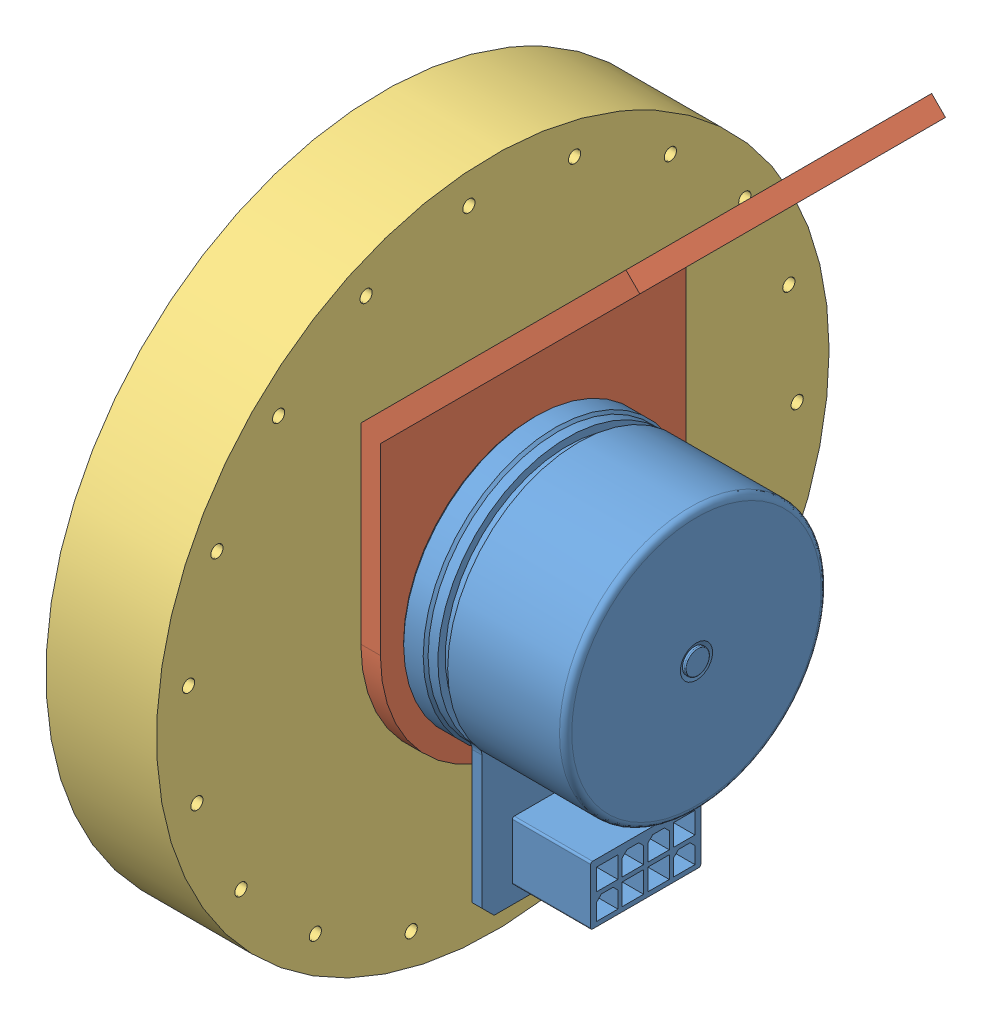
SolidWorks assembly SE_01_1_6000, configuration Default. Lengths in mm.
Overall size (82.11 148.01 146.64).
6 component instances, 4 part files, 11 mates.
Components (placement in the parent):
- SE_01_1_6001-1: SE_01_1_6001 [Default] at origin size (47.5 62.1 43.2)
- SE_01_1_6002-1: SE_01_1_6002 [Default] x (0 0 1) z (-1 0 0) size (50 99.69 45.63)
- SE_01_1_6003-1: SE_01_1_6003 [Default] at (-14.6 0 0) x (0 0.902596 -0.430488) z (-1 0 0) size (110 110 53.58)
- pan head cross recess screw_iso-1: pan head cross recess screw_iso [ISO 7045 - M2.5 x 8 - Z - 8N] at (-5.3 -5.5 9.5263) x (1 0 0) z (0 -0.797262 -0.603633) size (10.05 5 5)
- pan head cross recess screw_iso-2: pan head cross recess screw_iso [ISO 7045 - M2.5 x 8 - Z - 8N] at (-5.3 -5.5 -9.5263) x (1 0 0) z (0 0.462754 0.886487) size (10.05 5 5)
- pan head cross recess screw_iso-3: pan head cross recess screw_iso [ISO 7045 - M2.5 x 8 - Z - 8N] at (-5.3 11 0) size (10.05 5 5)
Mates (geometry in assembly coordinates):
- Coincident1: coincident anti-aligned: plane of SE_01_1_6001-1 through (0 0 0) normal (-1 0 0); plane of SE_01_1_6002-1 through (0 0 0) normal (1 0 0)
- Concentric1: concentric aligned: cylinder of SE_01_1_6001-1 through (-3.2 0 0) axis (1 0 0) radius 6; cylinder of SE_01_1_6002-1 through (-77.5303 0 0) axis (1 0 0) radius 6.2732
- Concentric2: concentric anti-aligned: cylinder of SE_01_1_6001-1 through (0 11 0) axis (-1 0 0) radius 1.25; cylinder of SE_01_1_6002-1 through (-77.5303 11 0) axis (1 0 0) radius 1.25
- Concentric3: concentric anti-aligned: cylinder of SE_01_1_6002-1 through (-77.5303 11 0) axis (1 0 0) radius 1.25; cylinder of pan head cross recess screw_iso-3 through (-30.7 11 0) axis (-1 0 0) radius 1.25
- Concentric4: concentric anti-aligned: cylinder of SE_01_1_6002-1 through (-77.5303 -5.5 -9.5263) axis (1 0 0) radius 1.25; cylinder of pan head cross recess screw_iso-2 through (-30.7 -5.5 -9.5263) axis (-1 0 0) radius 1.25
- Concentric5: concentric anti-aligned: cylinder of SE_01_1_6002-1 through (-77.5303 -5.5 9.5263) axis (1 0 0) radius 1.25; cylinder of pan head cross recess screw_iso-1 through (-30.7 -5.5 9.5263) axis (-1 0 0) radius 1.25
- Coincident2: coincident anti-aligned: plane of SE_01_1_6002-1 through (-3.2 0 0) normal (-1 0 0); plane of pan head cross recess screw_iso-3 through (-3.2 12.25 0) normal (1 0 0)
- Coincident3: coincident anti-aligned: plane of SE_01_1_6002-1 through (-3.2 0 0) normal (-1 0 0); plane of pan head cross recess screw_iso-2 through (-3.2 -4.3919 -10.1047) normal (1 0 0)
- Coincident4: coincident anti-aligned: plane of SE_01_1_6002-1 through (-3.2 0 0) normal (-1 0 0); plane of pan head cross recess screw_iso-1 through (-3.2 -6.2545 10.5229) normal (1 0 0)
- Concentric6: concentric aligned: cylinder of SE_01_1_6001-1 through (-20.1 0 0) axis (1 0 0) radius 2; cylinder of SE_01_1_6003-1 through (-22.6 0 0) axis (1 0 0) radius 2
- Coincident5: coincident anti-aligned: plane of SE_01_1_6001-1 through (-20.6 0 0) normal (-1 0 0); plane of SE_01_1_6003-1 through (-20.6 0 0) normal (1 0 0)
